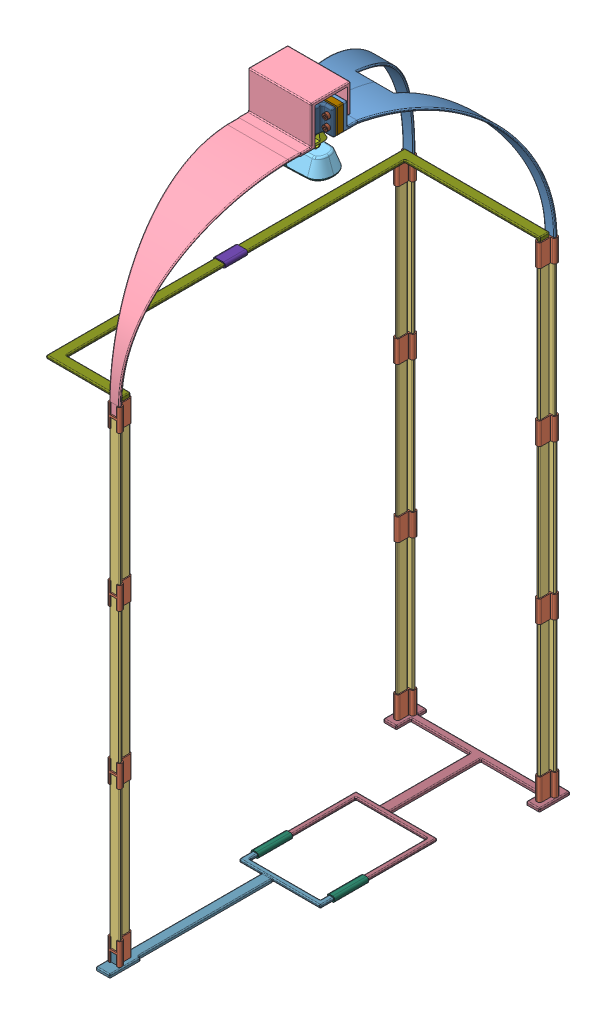
SolidWorks assembly cam-pied, configuration Défaut. Lengths in mm.
Overall size (156.53 671.2 384.16).
68 component instances, 17 part files, 139 mates.
Components (placement in the parent):
- cam-pied-droit-1-1: cam-pied-droit-1 [Défaut] at (-24.3914 -23.7361 180.8499) x (-1 0 0) z (0 0 -1) size (78.27 185 176.21)
  - cam-pied-droit-1: cam-pied-droit [Défaut] at (-220.0345 188.3747 308) size (156.53 186.65 177.66)
- cam-pied-droit-2-1: cam-pied-droit-2 [Défaut] at (-24.3914 -23.7361 180.8499) x (-1 0 0) z (0 0 -1) size (78.27 186.65 177.66)
  - cam-pied-droit-1: cam-pied-droit [Défaut] at (-220.0345 188.3747 308) size (156.53 186.65 177.66)
- cam-pied-joint-1: cam-pied-joint [Défaut] at (195.7432 4.6385 66.4499) x (1 0 0) z (0 1 0) size (12.2 16.4 22)
- cam-pied-joint-2: cam-pied-joint [Défaut] at (265.6432 2.6385 -292.5501) x (1 0 0) z (0 -1 0) size (12.2 16.4 22)
- cam-pied-joint-3: cam-pied-joint [Défaut] at (125.6432 2.6385 -292.7501) x (1 0 0) z (0 -1 0) size (12.2 16.4 22)
- cam-pied-joint-4: cam-pied-joint [Défaut] at (265.6432 -149.3615 -292.5501) x (1 0 0) z (0 -1 0) size (12.2 16.4 22)
- cam-pied-joint-5: cam-pied-joint [Défaut] at (125.8432 -301.3615 -292.7501) x (1 0 0) z (0 -1 0) size (12.2 16.4 22)
- cam-pied-joint-6: cam-pied-joint [Défaut] at (265.6432 -301.3615 -292.5501) x (1 0 0) z (0 -1 0) size (12.2 16.4 22)
- cam-pied-joint-7: cam-pied-joint [Défaut] at (125.6432 -149.3615 -292.7501) x (1 0 0) z (0 -1 0) size (12.2 16.4 22)
- cam-pied-joint-8: cam-pied-joint [Défaut] at (195.7432 -147.3615 66.4499) x (1 0 0) z (0 1 0) size (12.2 16.4 22)
- cam-pied-joint-9: cam-pied-joint [Défaut] at (195.7432 -299.3615 66.4499) x (1 0 0) z (0 1 0) size (12.2 16.4 22)
- cam-pied-montant-1: cam-pied-montant [Défaut] at (195.8432 -147.3615 66.3499) x (1 0 0) z (0 1 0) size (10 3 150)
- cam-pied-montant-2: cam-pied-montant [Défaut] at (195.6432 -299.3615 66.3499) x (1 0 0) z (0 1 0) size (10 3 150)
- cam-pied-montant-3: cam-pied-montant [Défaut] at (195.8432 -147.3615 58.6499) x (0 0 -1) z (0 1 0) size (10 3 150)
- cam-pied-montant-4: cam-pied-montant [Défaut] at (195.8432 -299.3615 58.6499) x (0 0 1) z (0 1 0) size (10 3 150)
- cam-pied-montant-5: cam-pied-montant [Défaut] at (265.7432 -299.3615 -284.7501) x (0 0 -1) z (0 1 0) size (10 3 150)
- cam-pied-montant-6: cam-pied-montant [Défaut] at (265.7432 -149.3615 -292.4501) x (1 0 0) z (0 -1 0) size (10 3 150)
- cam-pied-montant-7: cam-pied-montant [Défaut] at (125.7432 -147.3615 -285.1501) x (0 0 -1) z (0 1 0) size (10 3 150)
- cam-pied-montant-8: cam-pied-montant [Défaut] at (125.7432 -299.3615 -285.1501) x (0 0 1) z (0 1 0) size (10 3 150)
- cam-pied-montant-9: cam-pied-montant [Défaut] at (125.7432 -149.3615 -292.6501) x (1 0 0) z (0 -1 0) size (10 3 150)
- cam-pied-montant-10: cam-pied-montant [Défaut] at (265.5432 -147.3615 -292.4501) x (1 0 0) z (0 1 0) size (10 3 150)
- cam-pied-montant-11: cam-pied-montant [Défaut] at (125.5432 2.6385 -292.6501) x (1 0 0) z (0 -1 0) size (10 3 150)
- cam-pied-montant-12: cam-pied-montant [Défaut] at (265.7432 2.6385 -284.9501) x (0 0 -1) z (0 -1 0) size (10 3 150)
- cam-pied-gauche-1: cam-pied-gauche [Défaut] at (195.6432 164.6385 -99.1501) size (81.23 201.44 213.44)
- cam-c310-monte-1: cam-c310-monte [Défaut] at (194.893 183.199 -97.427) x (-1 0 0) z (0 1 0) size (71.5 31.83 69.48)
  - c310-1: c310 [Défaut] at (4.1302 -12.061 -110.284) x (-1 0 0) z (0 0 1) size (71.5 31.65 69.48)
    - c310-corps-1: c310-corps [Default] at (1.7129 6.6622 61.3001) size (71.27 31.35 30.56)
    - c310-cache-1: c310-cache [Default] at (1.7129 6.6622 59.0501) x (-1 0 0) z (0 0 -1) size (71.5 31.65 2.5)
    - clip-1-1: clip-1 [Default] at (4.1303 6.6622 81.7235) x (-1 0 0) z (0 0 1) size (43.19 23.62 48.27)
    - clip-2-1: clip-2 [Default] at (4.8803 2.4122 105.5985) x (-1 0 0) z (0 0 -1) size (36 14.88 39.47)
  - cam-mount-1-1: cam-mount-1 [Défaut] at (-0.7501 -29.7231 -6.0605) size (62 8 37)
  - cam-mount-2-1: cam-mount-2 [Défaut] at (-0.7501 -22.2204 -18.5605) size (62 19.5 37)
  - vis-chc-1: vis-chc [Vis CHC M3x10] at (25.2468 -19.2204 -1.0605) x (1 0 0) z (0 0 1) size (5.5 13 5.5)
  - vis-chc-2: vis-chc [Vis CHC M3x10] at (25.2468 -19.2204 -11.0605) x (1 0 0) z (0 0 1) size (5.5 13 5.5)
  - ecrou-h-1: ecrou-h [6012 HU M3] at (25.2468 -26.7231 -11.0605) x (0.5 0 -0.866025) z (0.866025 0 0.5) size (5.5 2.4 6.35)
  - vis-chc-3: vis-chc [Vis CHC M3x10] at (-26.7501 -19.2204 -1.0605) x (0.999999 0 -0.001191) z (0.001191 0 0.999999) size (5.5 13 5.5)
  - vis-chc-4: vis-chc [Vis CHC M3x10] at (-26.7501 -19.2204 -11.0605) x (0.814665 0 0.579932) z (-0.579932 0 0.814665) size (5.5 13 5.5)
  - ecrou-h-2: ecrou-h [6012 HU M3] at (25.2468 -26.7231 -1.0605) x (0.5 0 -0.866025) z (0.866025 0 0.5) size (5.5 2.4 6.35)
  - ecrou-h-3: ecrou-h [6012 HU M3] at (-26.7501 -26.7231 -1.0605) x (0.5 0 -0.866025) z (0.866025 0 0.5) size (5.5 2.4 6.35)
  - ecrou-h-4: ecrou-h [6012 HU M3] at (-26.7501 -26.7231 -11.0605) x (0.5 0 0.866025) z (-0.866025 0 0.5) size (5.5 2.4 6.35)
- vis-chc-1: vis-chc [Vis CHC M3x10] at (179.6432 182.1385 -134.1501) x (0.923728 0.383049 0) z (-0.383049 0.923728 0) size (5.5 13 5.5)
- vis-chc-2: vis-chc [Vis CHC M3x10] at (179.6432 172.1385 -131.1501) x (0.923728 0.383049 0) z (-0.383049 0.923728 0) size (5.5 13 5.5)
- vis-chc-3: vis-chc [Vis CHC M3x10] at (211.6432 172.1385 -131.1501) x (0.923728 0.383049 0) z (-0.383049 0.923728 0) size (5.5 13 5.5)
- vis-chc-4: vis-chc [Vis CHC M3x10] at (211.6432 182.1385 -134.1501) x (0.923728 0.383049 0) z (-0.383049 0.923728 0) size (5.5 13 5.5)
- ecrou-h-1: ecrou-h [6012 HU M3] at (211.6432 172.1385 -121.7501) x (-0.866025 0.5 0) z (0.5 0.866025 0) size (5.5 2.4 6.35)
- ecrou-h-2: ecrou-h [6012 HU M3] at (179.6432 172.1385 -121.7501) x (0 1 0) z (1 0 0) size (5.5 2.4 6.35)
- ecrou-h-3: ecrou-h [6012 HU M3] at (179.6432 182.1385 -121.7501) x (-0.866025 0.5 0) z (0.5 0.866025 0) size (5.5 2.4 6.35)
- ecrou-h-4: ecrou-h [6012 HU M3] at (211.6432 182.1385 -121.7501) x (0 1 0) z (1 0 0) size (5.5 2.4 6.35)
- cam-pied-joint-10: cam-pied-joint [Défaut] at (195.7432 -451.3615 66.4499) x (1 0 0) z (0 1 0) size (12.2 16.4 22)
- cam-pied-joint-11: cam-pied-joint [Défaut] at (125.7432 -453.3615 -292.7501) x (1 0 0) z (0 -1 0) size (12.2 16.4 22)
- cam-pied-joint-12: cam-pied-joint [Défaut] at (265.7432 -453.3615 -292.7501) x (1 0 0) z (0 -1 0) size (12.2 16.4 22)
- cam-socle-droit-2: cam-socle-droit [Défaut] at (195.8432 -463.3615 -292.6501) x (0 0 1) z (-1 0 0) size (185 13 154)
- cam-socle-gauche-1: cam-socle-gauche [Défaut] at (195.8432 -463.3615 67.8499) x (0 0 -1) z (1 0 0) size (185 14 80)
- cam-socle-joint-1: cam-socle-joint [Défaut] at (245.7432 -463.9615 -105.6501) size (7.2 5.2 33.5)
- cam-socle-joint-2: cam-socle-joint [Défaut] at (170.7432 -463.9615 -105.6501) size (7.2 5.2 33.5)
- cam-contreventement-1-2: cam-contreventement-1 [Défaut] at (549.3332 86.3011 -61.2162) x (0 0 -1) z (-1 0 0) size (175.8 14 73.11)
  - cam-contreventement-1: cam-contreventement [Défaut] at (218.7339 70.6625 353.6) size (353.6 14 143)
- cam-contreventement-2-1: cam-contreventement-2 [Défaut] at (549.3432 86.3011 -61.2162) x (0 0 -1) z (-1 0 0) size (175.8 14 143)
  - cam-contreventement-1: cam-contreventement [Défaut] at (218.7339 70.6625 353.6) size (353.6 14 143)
- cam-contreventement-joint-1: cam-contreventement-joint [Défaut] at (129.2332 17.1385 -112.1501) size (12 5 22)
- cam-pied-montant-13: cam-pied-montant [Défaut] at (195.8432 -451.3615 66.3499) x (1 0 0) z (0 1 0) size (10 3 150)
- cam-pied-montant-14: cam-pied-montant [Défaut] at (195.8432 -451.3615 58.8499) x (0 0 1) z (0 1 0) size (10 3 150)
- cam-pied-montant-15: cam-pied-montant [Défaut] at (125.9432 -451.3615 -292.6501) x (1 0 0) z (0 1 0) size (10 3 150)
- cam-pied-montant-16: cam-pied-montant [Défaut] at (125.8432 -451.3615 -284.9501) x (0 0 1) z (0 1 0) size (10 3 150)
- cam-pied-montant-17: cam-pied-montant [Défaut] at (265.7432 -451.3615 -292.4501) x (1 0 0) z (0 1 0) size (10 3 150)
- cam-pied-montant-18: cam-pied-montant [Défaut] at (265.7432 -451.3615 -284.9501) x (0 0 1) z (0 1 0) size (10 3 150)
Mates (geometry in assembly coordinates):
- Coïncidente18: coincident anti-aligned: plane of cam-pied-partie3-1/cam-pied-droit-1 through (120.6432 14.6385 -294.1501) normal (0 0 -1); plane of cam-pied-joint-v3-2 through (269.7432 14.6385 -294.1501) normal (0 0 1)
- Coïncidente19: coincident anti-aligned: plane of cam-pied-partie4-1/cam-pied-droit-1 through (120.6432 14.6385 -291.1501) normal (0 0 1); plane of cam-pied-joint-v3-3 through (121.5432 14.6385 -291.1501) normal (0 0 -1)
- Distance5: distance = 0.1 mm anti-aligned: plane of cam-pied-joint-v3-3 through (130.7432 14.6385 -292.1501) normal (-1 0 0); plane of cam-pied-partie4-1/cam-pied-droit-1 through (130.6432 14.6385 -127.1501) normal (1 0 0)
- Distance6: distance = 0.1 mm anti-aligned: plane of cam-pied-joint-v3-2 through (270.7432 14.6385 -291.9501) normal (-1 0 0); plane of cam-pied-partie3-1/cam-pied-droit-1 through (270.6432 164.6385 -127.1501) normal (1 0 0)
- Coïncidente49: coincident anti-aligned: plane of cam-pied-joint-1 through (191.6432 -7.3615 64.8499) normal (0 0 1); plane of cam-pied-montant-1 through (191.8432 2.6385 64.8499) normal (0 0 -1)
- Coïncidente50: coincident anti-aligned: plane of cam-pied-joint-1 through (200.8432 -7.3615 65.8499) normal (-1 0 0); plane of cam-pied-montant-1 through (200.8432 2.6385 65.8499) normal (1 0 0)
- Coïncidente51: coincident anti-aligned: plane of cam-pied-joint-1 through (199.8432 2.6385 65.8499) normal (0 -1 0); plane of cam-pied-montant-1 through (199.8432 2.6385 65.8499) normal (0 1 0)
- Coïncidente52: coincident anti-aligned: plane of cam-pied-joint-8 through (191.6432 -137.3615 64.8499) normal (0 0 1); plane of cam-pied-montant-1 through (191.8432 2.6385 64.8499) normal (0 0 -1)
- Coïncidente53: coincident anti-aligned: plane of cam-pied-joint-8 through (200.8432 -137.3615 65.8499) normal (-1 0 0); plane of cam-pied-montant-1 through (200.8432 2.6385 65.8499) normal (1 0 0)
- Coïncidente54: coincident anti-aligned: plane of cam-pied-joint-8 through (199.8432 -147.3615 65.8499) normal (0 1 0); plane of cam-pied-montant-1 through (199.8432 -147.3615 65.8499) normal (0 -1 0)
- Coïncidente55: coincident anti-aligned: plane of cam-pied-joint-1 through (197.3432 -7.3615 62.8499) normal (-1 0 0); plane of cam-pied-montant-3 through (197.3432 2.6385 62.6499) normal (1 0 0)
- Coïncidente56: coincident anti-aligned: plane of cam-pied-joint-1 through (195.1432 -7.3615 53.6499) normal (0 0 1); plane of cam-pied-montant-3 through (195.3432 2.6385 53.6499) normal (0 0 -1)
- Coïncidente57: coincident anti-aligned: plane of cam-pied-joint-1 through (199.8432 2.6385 65.8499) normal (0 -1 0); plane of cam-pied-montant-3 through (195.3432 2.6385 54.6499) normal (0 1 0)
- Coïncidente58: coincident anti-aligned: plane of cam-pied-joint-8 through (191.6432 -159.3615 64.8499) normal (0 0 1); plane of cam-pied-montant-2 through (191.6432 -149.3615 64.8499) normal (0 0 -1)
- Coïncidente59: coincident anti-aligned: plane of cam-pied-joint-8 through (190.6432 -159.3615 67.0499) normal (1 0 0); plane of cam-pied-montant-2 through (190.6432 -149.3615 65.8499) normal (-1 0 0)
- Coïncidente60: coincident anti-aligned: plane of cam-pied-joint-8 through (199.8432 -149.3615 65.8499) normal (0 -1 0); plane of cam-pied-montant-2 through (199.6432 -149.3615 65.8499) normal (0 1 0)
- Coïncidente61: coincident anti-aligned: plane of cam-pied-joint-9 through (191.6432 -289.3615 64.8499) normal (0 0 1); plane of cam-pied-montant-2 through (191.6432 -149.3615 64.8499) normal (0 0 -1)
- Coïncidente62: coincident anti-aligned: plane of cam-pied-joint-9 through (190.6432 -289.3615 67.0499) normal (1 0 0); plane of cam-pied-montant-2 through (190.6432 -149.3615 65.8499) normal (-1 0 0)
- Coïncidente63: coincident anti-aligned: plane of cam-pied-joint-9 through (199.8432 -299.3615 65.8499) normal (0 1 0); plane of cam-pied-montant-2 through (199.6432 -299.3615 65.8499) normal (0 -1 0)
- Coïncidente64: coincident anti-aligned: plane of cam-pied-joint-8 through (197.3432 -159.3615 62.8499) normal (-1 0 0); plane of cam-pied-montant-4 through (197.3432 -149.3615 54.6499) normal (1 0 0)
- Coïncidente65: coincident anti-aligned: plane of cam-pied-joint-8 through (195.1432 -159.3615 53.6499) normal (0 0 1); plane of cam-pied-montant-4 through (196.3432 -149.3615 53.6499) normal (0 0 -1)
- Coïncidente66: coincident anti-aligned: plane of cam-pied-joint-8 through (199.8432 -149.3615 65.8499) normal (0 -1 0); plane of cam-pied-montant-4 through (196.3432 -149.3615 62.6499) normal (0 1 0)
- Coïncidente67: coincident anti-aligned: plane of cam-pied-droit-2-1/cam-pied-droit-1 through (120.6432 4.6385 -291.1501) normal (0 -1 0); plane of cam-pied-joint-3 through (129.7432 4.6385 -292.1501) normal (0 1 0)
- Coïncidente68: coincident anti-aligned: plane of cam-pied-droit-1-1/cam-pied-droit-1 through (120.6432 4.6385 -291.1501) normal (0 -1 0); plane of cam-pied-joint-2 through (269.7432 4.6385 -291.9501) normal (0 1 0)
- Coïncidente69: coincident anti-aligned: plane of cam-pied-joint-2 through (267.2432 -7.3615 -288.9501) normal (-1 0 0); plane of cam-pied-montant-12 through (267.2432 -147.3615 -280.9501) normal (1 0 0)
- Coïncidente70: coincident anti-aligned: plane of cam-pied-joint-2 through (265.0432 -7.3615 -289.9501) normal (0 0 1); plane of cam-pied-montant-12 through (266.2432 -147.3615 -289.9501) normal (0 0 -1)
- Coïncidente71: coincident anti-aligned: plane of cam-pied-joint-2 through (269.7432 2.6385 -291.9501) normal (0 -1 0); plane of cam-pied-montant-12 through (266.2432 2.6385 -288.9501) normal (0 1 0)
- Coïncidente72: coincident anti-aligned: plane of cam-pied-joint-2 through (261.5432 -7.3615 -290.9501) normal (0 0 -1); plane of cam-pied-montant-10 through (261.5432 2.6385 -290.9501) normal (0 0 1)
- Coïncidente73: coincident anti-aligned: plane of cam-pied-joint-2 through (260.5432 -7.3615 -293.1501) normal (1 0 0); plane of cam-pied-montant-10 through (260.5432 2.6385 -292.9501) normal (-1 0 0)
- Coïncidente74: coincident anti-aligned: plane of cam-pied-joint-2 through (269.7432 2.6385 -291.9501) normal (0 -1 0); plane of cam-pied-montant-10 through (269.5432 2.6385 -292.9501) normal (0 1 0)
- Coïncidente75: coincident anti-aligned: plane of cam-pied-joint-4 through (261.5432 -159.3615 -290.9501) normal (0 0 -1); plane of cam-pied-montant-10 through (261.5432 2.6385 -290.9501) normal (0 0 1)
- Coïncidente76: coincident anti-aligned: plane of cam-pied-joint-4 through (260.5432 -159.3615 -293.1501) normal (1 0 0); plane of cam-pied-montant-10 through (260.5432 2.6385 -292.9501) normal (-1 0 0)
- Coïncidente77: coincident anti-aligned: plane of cam-pied-joint-4 through (269.7432 -147.3615 -291.9501) normal (0 1 0); plane of cam-pied-montant-10 through (269.5432 -147.3615 -292.9501) normal (0 -1 0)
- Coïncidente78: coincident anti-aligned: plane of cam-pied-joint-4 through (261.5432 -159.3615 -290.9501) normal (0 0 -1); plane of cam-pied-montant-6 through (261.7432 -299.3615 -290.9501) normal (0 0 1)
- Coïncidente79: coincident anti-aligned: plane of cam-pied-joint-4 through (270.7432 -159.3615 -291.9501) normal (-1 0 0); plane of cam-pied-montant-6 through (270.7432 -299.3615 -291.9501) normal (1 0 0)
- Coïncidente80: coincident anti-aligned: plane of cam-pied-joint-4 through (269.7432 -149.3615 -291.9501) normal (0 -1 0); plane of cam-pied-montant-6 through (269.7432 -149.3615 -291.9501) normal (0 1 0)
- Coïncidente81: coincident anti-aligned: plane of cam-pied-joint-6 through (261.5432 -289.3615 -290.9501) normal (0 0 -1); plane of cam-pied-montant-6 through (261.7432 -299.3615 -290.9501) normal (0 0 1)
- Coïncidente82: coincident anti-aligned: plane of cam-pied-joint-6 through (270.7432 -289.3615 -291.9501) normal (-1 0 0); plane of cam-pied-montant-6 through (270.7432 -299.3615 -291.9501) normal (1 0 0)
- Coïncidente83: coincident anti-aligned: plane of cam-pied-joint-6 through (269.7432 -299.3615 -291.9501) normal (0 1 0); plane of cam-pied-montant-6 through (269.7432 -299.3615 -291.9501) normal (0 -1 0)
- Coïncidente84: coincident anti-aligned: plane of cam-pied-joint-4 through (267.2432 -159.3615 -288.9501) normal (-1 0 0); plane of cam-pied-montant-5 through (267.2432 -149.3615 -280.7501) normal (1 0 0)
- Coïncidente85: coincident anti-aligned: plane of cam-pied-joint-4 through (265.0432 -159.3615 -279.7501) normal (0 0 -1); plane of cam-pied-montant-5 through (265.2432 -149.3615 -279.7501) normal (0 0 1)
- Coïncidente86: coincident anti-aligned: plane of cam-pied-joint-4 through (269.7432 -149.3615 -291.9501) normal (0 -1 0); plane of cam-pied-montant-5 through (265.2432 -149.3615 -288.7501) normal (0 1 0)
- Coïncidente87: coincident anti-aligned: plane of cam-pied-joint-3 through (121.5432 -7.3615 -291.1501) normal (0 0 -1); plane of cam-pied-montant-11 through (121.5432 -147.3615 -291.1501) normal (0 0 1)
- Coïncidente88: coincident anti-aligned: plane of cam-pied-joint-3 through (120.5432 -7.3615 -293.3501) normal (1 0 0); plane of cam-pied-montant-11 through (120.5432 -147.3615 -292.1501) normal (-1 0 0)
- Coïncidente89: coincident anti-aligned: plane of cam-pied-joint-3 through (129.7432 2.6385 -292.1501) normal (0 -1 0); plane of cam-pied-montant-11 through (129.5432 2.6385 -292.1501) normal (0 1 0)
- Coïncidente90: coincident anti-aligned: plane of cam-pied-joint-7 through (120.5432 -137.3615 -293.3501) normal (1 0 0); plane of cam-pied-montant-11 through (120.5432 -147.3615 -292.1501) normal (-1 0 0)
- Coïncidente91: coincident anti-aligned: plane of cam-pied-joint-7 through (121.5432 -137.3615 -291.1501) normal (0 0 -1); plane of cam-pied-montant-11 through (121.5432 -147.3615 -291.1501) normal (0 0 1)
- Coïncidente92: coincident anti-aligned: plane of cam-pied-joint-7 through (129.7432 -147.3615 -292.1501) normal (0 1 0); plane of cam-pied-montant-11 through (129.5432 -147.3615 -292.1501) normal (0 -1 0)
- Coïncidente93: coincident anti-aligned: plane of cam-pied-joint-3 through (127.2432 -7.3615 -289.1501) normal (-1 0 0); plane of cam-pied-montant-7 through (127.2432 2.6385 -281.1501) normal (1 0 0)
- Coïncidente94: coincident anti-aligned: plane of cam-pied-joint-3 through (125.0432 -7.3615 -290.1501) normal (0 0 1); plane of cam-pied-montant-7 through (125.2432 2.6385 -290.1501) normal (0 0 -1)
- Coïncidente95: coincident anti-aligned: plane of cam-pied-joint-3 through (129.7432 2.6385 -292.1501) normal (0 -1 0); plane of cam-pied-montant-7 through (125.2432 2.6385 -289.1501) normal (0 1 0)
- Coïncidente96: coincident anti-aligned: plane of cam-pied-joint-7 through (127.2432 -159.3615 -289.1501) normal (-1 0 0); plane of cam-pied-montant-8 through (127.2432 -149.3615 -289.1501) normal (1 0 0)
- Coïncidente97: coincident anti-aligned: plane of cam-pied-joint-7 through (125.0432 -159.3615 -290.1501) normal (0 0 1); plane of cam-pied-montant-8 through (126.2432 -149.3615 -290.1501) normal (0 0 -1)
- Coïncidente98: coincident anti-aligned: plane of cam-pied-joint-7 through (129.7432 -149.3615 -292.1501) normal (0 -1 0); plane of cam-pied-montant-8 through (126.2432 -149.3615 -281.1501) normal (0 1 0)
- Coïncidente99: coincident anti-aligned: plane of cam-pied-joint-7 through (121.5432 -159.3615 -291.1501) normal (0 0 -1); plane of cam-pied-montant-9 through (121.7432 -299.3615 -291.1501) normal (0 0 1)
- Coïncidente100: coincident anti-aligned: plane of cam-pied-joint-7 through (130.7432 -159.3615 -292.1501) normal (-1 0 0); plane of cam-pied-montant-9 through (130.7432 -299.3615 -292.1501) normal (1 0 0)
- Coïncidente101: coincident anti-aligned: plane of cam-pied-joint-7 through (129.7432 -149.3615 -292.1501) normal (0 -1 0); plane of cam-pied-montant-9 through (129.7432 -149.3615 -292.1501) normal (0 1 0)
- Coaxiale5: concentric aligned: cylinder of cam-pied-droit-2-1/cam-pied-droit-1 through (179.6432 182.1385 -127.1501) axis (0 0 -1) radius 1.6; cylinder of cam-pied-gauche-1 through (179.6432 182.1385 -126.6246) axis (0 0 -1) radius 1.6
- Coïncidente103: coincident anti-aligned: plane of cam-pied-droit-2-1/cam-pied-droit-1 through (195.6432 164.6385 -131.1501) normal (0 0 -1); plane of cam-pied-gauche-1 through (226.6432 176.6385 -131.1501) normal (0 0 1)
- Coaxiale6: concentric aligned: cylinder of cam-pied-droit-1-1/cam-pied-droit-1 through (211.6432 182.1385 -127.1501) axis (0 0 -1) radius 1.6; cylinder of cam-pied-gauche-1 through (211.6432 182.1385 -126.6246) axis (0 0 -1) radius 1.6
- Coïncidente104: coincident anti-aligned: plane of cam-pied-droit-1-1/cam-pied-droit-1 through (195.6432 164.6385 -131.1501) normal (0 0 -1); plane of cam-pied-gauche-1 through (226.6432 176.6385 -131.1501) normal (0 0 1)
- Coïncidente105: coincident anti-aligned: plane of cam-pied-droit-1-1/cam-pied-droit-1 through (195.6432 -23.7361 180.8499) normal (-1 0 0); plane of cam-pied-droit-2-1/cam-pied-droit-1 through (195.6432 -23.7361 180.8499) normal (1 0 0)
- Coïncidente106: coincident anti-aligned: plane of cam-pied-joint-1 through (191.6432 14.6385 64.8499) normal (0 0 1); plane of cam-pied-gauche-1 through (270.6432 14.6385 64.8499) normal (0 0 -1)
- Coïncidente107: coincident anti-aligned: plane of cam-pied-joint-1 through (190.6432 14.6385 67.0499) normal (1 0 0); plane of cam-pied-gauche-1 through (190.6432 -263.8698 -134.1501) normal (-1 0 0)
- Coïncidente108: coincident anti-aligned: plane of cam-pied-joint-1 through (199.8432 4.6385 65.8499) normal (0 1 0); plane of cam-pied-gauche-1 through (270.6432 4.6385 64.8499) normal (0 -1 0)
- Coïncidente109: coincident anti-aligned: plane of cam-pied-joint-5 through (121.7432 -289.3615 -291.1501) normal (0 0 -1); plane of cam-pied-montant-9 through (121.7432 -299.3615 -291.1501) normal (0 0 1)
- Coïncidente110: coincident anti-aligned: plane of cam-pied-joint-5 through (120.7432 -289.3615 -293.3501) normal (1 0 0); plane of cam-pied-montant-9 through (120.7432 -299.3615 -292.1501) normal (-1 0 0)
- Coïncidente111: coincident anti-aligned: plane of cam-pied-joint-5 through (129.9432 -299.3615 -292.1501) normal (0 1 0); plane of cam-pied-montant-9 through (129.7432 -299.3615 -292.1501) normal (0 -1 0)
- Coïncidente112: coincident anti-aligned: plane of cam-pied-droit-1-1/cam-pied-droit-1 through (195.6432 164.6385 -127.1501) normal (0 0 1); plane of cam-c310-monte-1/cam-mount-1-1 through (195.6432 177.1385 -127.1501) normal (0 0 -1)
- Coaxiale7: concentric anti-aligned: cylinder of cam-pied-gauche-1 through (211.6432 182.1385 -126.6246) axis (0 0 -1) radius 1.6; cylinder of cam-c310-monte-1/cam-mount-1-1 through (211.6432 182.1385 -127.1501) axis (0 0 1) radius 1.6
- Coaxiale8: concentric anti-aligned: cylinder of cam-pied-gauche-1 through (179.6432 182.1385 -126.6246) axis (0 0 -1) radius 1.6; cylinder of cam-c310-monte-1/cam-mount-1-1 through (179.6432 182.1385 -127.1501) axis (0 0 1) radius 1.6
- Coaxiale9: concentric aligned: cylinder of cam-pied-gauche-1 through (211.6432 182.1385 -126.6246) axis (0 0 -1) radius 1.6; cylinder of vis-chc-4 through (211.6432 182.1385 -124.1501) axis (0 0 -1) radius 1.5
- Coaxiale10: concentric aligned: cylinder of cam-pied-gauche-1 through (179.6432 182.1385 -126.6246) axis (0 0 -1) radius 1.6; cylinder of vis-chc-1 through (179.6432 182.1385 -124.1501) axis (0 0 -1) radius 1.5
- Coaxiale11: concentric aligned: cylinder of cam-pied-droit-2-1/cam-pied-droit-1 through (179.6432 172.1385 -127.1501) axis (0 0 -1) radius 1.6; cylinder of vis-chc-2 through (179.6432 172.1385 -121.1501) axis (0 0 -1) radius 1.5
- Coaxiale12: concentric aligned: cylinder of cam-pied-droit-1-1/cam-pied-droit-1 through (211.6432 172.1385 -127.1501) axis (0 0 -1) radius 1.6; cylinder of vis-chc-3 through (211.6432 172.1385 -121.1501) axis (0 0 -1) radius 1.5
- Coïncidente113: coincident anti-aligned: plane of cam-pied-gauche-1 through (195.6432 164.6385 -134.1501) normal (0 0 -1); plane of vis-chc-4 through (211.6432 182.1385 -134.1501) normal (0 0 1)
- Coïncidente114: coincident anti-aligned: plane of cam-pied-gauche-1 through (195.6432 164.6385 -134.1501) normal (0 0 -1); plane of vis-chc-1 through (179.6432 182.1385 -134.1501) normal (0 0 1)
- Coïncidente115: coincident anti-aligned: plane of cam-pied-droit-2-1/cam-pied-droit-1 through (195.6432 164.6385 -131.1501) normal (0 0 -1); plane of vis-chc-2 through (179.6432 172.1385 -131.1501) normal (0 0 1)
- Coïncidente116: coincident anti-aligned: plane of cam-pied-droit-1-1/cam-pied-droit-1 through (195.6432 164.6385 -131.1501) normal (0 0 -1); plane of vis-chc-3 through (211.6432 172.1385 -131.1501) normal (0 0 1)
- Coïncidente117: coincident anti-aligned: plane of cam-c310-monte-1/cam-mount-1-1 through (195.6432 177.1385 -124.1501) normal (0 0 1); plane of ecrou-h-4 through (210.0554 184.8885 -124.1501) normal (0 0 -1)
- Coaxiale14: concentric aligned: cylinder of cam-c310-monte-1/cam-mount-1-1 through (211.6432 182.1385 -127.1501) axis (0 0 1) radius 1.6; cylinder of ecrou-h-4 through (211.6432 182.1385 -124.1501) axis (0 0 1) radius 1.2295
- Parallèle1: parallel anti-aligned: plane of cam-c310-monte-1/cam-mount-1-1 through (213.3932 179.1074 -124.1501) normal (-0.866025 0.5 0); plane of ecrou-h-4 through (213.2309 179.3885 -124.1501) normal (0.866025 -0.5 0)
- Coïncidente119: coincident anti-aligned: plane of cam-c310-monte-1/cam-mount-1-1 through (195.6432 177.1385 -124.1501) normal (0 0 1); plane of ecrou-h-1 through (208.4677 172.1385 -124.1501) normal (0 0 -1)
- Coaxiale15: concentric anti-aligned: cylinder of vis-chc-3 through (211.6432 172.1385 -121.1501) axis (0 0 -1) radius 1.5; cylinder of ecrou-h-1 through (211.6432 172.1385 -124.1501) axis (0 0 1) radius 1.2295
- Parallèle2: parallel anti-aligned: plane of cam-c310-monte-1/cam-mount-1-1 through (213.3932 175.1696 -124.1501) normal (0 -1 0); plane of ecrou-h-1 through (213.2309 174.8885 -124.1501) normal (0 1 0)
- Coïncidente121: coincident anti-aligned: plane of cam-c310-monte-1/cam-mount-1-1 through (195.6432 177.1385 -124.1501) normal (0 0 1); plane of ecrou-h-2 through (178.0554 174.8885 -124.1501) normal (0 0 -1)
- Coaxiale16: concentric anti-aligned: cylinder of vis-chc-2 through (179.6432 172.1385 -121.1501) axis (0 0 -1) radius 1.5; cylinder of ecrou-h-2 through (179.6432 172.1385 -124.1501) axis (0 0 1) radius 1.2295
- Parallèle3: parallel anti-aligned: plane of cam-c310-monte-1/cam-mount-1-1 through (183.1432 172.1385 -124.1501) normal (-0.866025 -0.5 0); plane of ecrou-h-2 through (182.8186 172.1385 -124.1501) normal (0.866025 0.5 0)
- Coïncidente124: coincident anti-aligned: plane of cam-c310-monte-1/cam-mount-1-1 through (195.6432 177.1385 -124.1501) normal (0 0 1); plane of ecrou-h-3 through (176.4677 182.1385 -124.1501) normal (0 0 -1)
- Coaxiale17: concentric anti-aligned: cylinder of vis-chc-1 through (179.6432 182.1385 -124.1501) axis (0 0 -1) radius 1.5; cylinder of ecrou-h-3 through (179.6432 182.1385 -124.1501) axis (0 0 1) radius 1.2295
- Parallèle4: parallel anti-aligned: plane of cam-c310-monte-1/cam-mount-1-1 through (183.1432 182.1385 -124.1501) normal (-0.866025 -0.5 0); plane of ecrou-h-3 through (182.8186 182.1385 -124.1501) normal (0.866025 0.5 0)
- Coïncidente156: coincident anti-aligned: plane of cam-socle-droit-2 through (129.8432 -453.3615 -291.1501) normal (0 0 1); plane of cam-pied-joint-11 through (121.6432 -463.3615 -291.1501) normal (0 0 -1)
- Coïncidente158: coincident anti-aligned: plane of cam-socle-droit-2 through (127.3432 -453.3615 -288.1501) normal (1 0 0); plane of cam-pied-joint-11 through (127.3432 -463.3615 -289.1501) normal (-1 0 0)
- Coïncidente160: coincident anti-aligned: plane of cam-pied-joint-10 through (191.6432 -463.3615 64.8499) normal (0 0 1); plane of cam-socle-gauche-1 through (191.8432 -452.3615 64.8499) normal (0 0 -1)
- Coïncidente161: coincident anti-aligned: plane of cam-pied-joint-10 through (197.3432 -463.3615 62.8499) normal (-1 0 0); plane of cam-socle-gauche-1 through (197.3432 -452.3615 61.8499) normal (1 0 0)
- Coïncidente162: coincident anti-aligned: plane of cam-pied-joint-10 through (199.8432 -463.3615 65.8499) normal (0 -1 0); plane of cam-socle-gauche-1 through (195.8432 -463.3615 67.8499) normal (0 1 0)
- Coïncidente163: coincident anti-aligned: plane of cam-pied-joint-1 through (197.3432 14.6385 62.8499) normal (-1 0 0); plane of cam-contreventement-1-2/cam-contreventement-1 through (197.3432 15.6385 -279.9501) normal (1 0 0)
- Coïncidente164: coincident anti-aligned: plane of cam-pied-joint-1 through (199.8432 4.6385 65.8499) normal (0 1 0); plane of cam-contreventement-1-2/cam-contreventement-1 through (265.2332 4.6385 -288.9501) normal (0 -1 0)
- Coïncidente166: coincident anti-aligned: plane of cam-pied-joint-1 through (195.1432 14.6385 53.6499) normal (0 0 1); plane of cam-contreventement-1-2/cam-contreventement-1 through (197.3432 18.6385 53.6499) normal (0 0 -1)
- Coïncidente167: coincident anti-aligned: plane of cam-pied-joint-2 through (269.7432 4.6385 -291.9501) normal (0 1 0); plane of cam-contreventement-2-1/cam-contreventement-1 through (265.2432 4.6385 -288.9501) normal (0 -1 0)
- Coïncidente168: coincident anti-aligned: plane of cam-pied-joint-2 through (267.2432 14.6385 -288.9501) normal (-1 0 0); plane of cam-contreventement-2-1/cam-contreventement-1 through (267.2432 18.6385 -279.9501) normal (1 0 0)
- Coïncidente169: coincident anti-aligned: plane of cam-pied-joint-3 through (125.0432 14.6385 -279.9501) normal (0 0 -1); plane of cam-contreventement-2-1/cam-contreventement-1 through (126.2432 4.6385 -279.9501) normal (0 0 1)
- Coïncidente171: coincident anti-aligned: plane of cam-contreventement-1-2/cam-contreventement-1 through (549.3332 86.3011 -112.1501) normal (0 0 -1); plane of cam-contreventement-joint-1 through (133.2332 17.6385 -112.1501) normal (0 0 1)
- Coïncidente172: coincident anti-aligned: plane of cam-contreventement-1-2/cam-contreventement-1 through (195.7332 18.6385 -279.9501) normal (0 1 0); plane of cam-contreventement-joint-1 through (125.2332 18.6385 -102.1501) normal (0 -1 0)
- Coïncidente173: coincident anti-aligned: plane of cam-contreventement-1-2/cam-contreventement-1 through (134.2332 18.6385 63.6499) normal (1 0 0); plane of cam-contreventement-joint-1 through (134.2332 17.6385 -102.1501) normal (-1 0 0)
- Coïncidente174: coincident anti-aligned: plane of cam-pied-joint-11 through (129.8432 -453.3615 -292.1501) normal (0 -1 0); plane of cam-socle-droit-2 through (121.8432 -453.3615 -293.1501) normal (0 1 0)
- Coïncidente175: coincident anti-aligned: plane of cam-socle-droit-2 through (168.3432 -462.3615 -192.6501) normal (0 1 0); plane of cam-socle-joint-1 through (244.1432 -462.3615 -129.1501) normal (0 -1 0)
- Coïncidente176: coincident anti-aligned: plane of cam-socle-droit-2 through (248.3432 -462.3615 -192.6501) normal (1 0 0); plane of cam-socle-joint-1 through (248.3432 -463.3615 -129.1501) normal (-1 0 0)
- Coïncidente177: coincident anti-aligned: plane of cam-socle-droit-2 through (195.8432 -463.3615 -119.1501) normal (0 0 1); plane of cam-socle-joint-1 through (247.3432 -463.3615 -119.1501) normal (0 0 -1)
- Coïncidente178: coincident anti-aligned: plane of cam-socle-droit-2 through (168.3432 -462.3615 -192.6501) normal (0 1 0); plane of cam-socle-joint-2 through (169.1432 -462.3615 -129.1501) normal (0 -1 0)
- Coïncidente179: coincident anti-aligned: plane of cam-socle-droit-2 through (195.8432 -463.3615 -119.1501) normal (0 0 1); plane of cam-socle-joint-2 through (172.3432 -463.3615 -119.1501) normal (0 0 -1)
- Coïncidente180: coincident anti-aligned: plane of cam-socle-droit-2 through (173.3432 -462.3615 -119.1501) normal (1 0 0); plane of cam-socle-joint-2 through (173.3432 -463.3615 -129.1501) normal (-1 0 0)
- Coïncidente183: coincident anti-aligned: plane of cam-pied-joint-9 through (199.8432 -301.3615 65.8499) normal (0 -1 0); plane of cam-pied-montant-13 through (199.8432 -301.3615 65.8499) normal (0 1 0)
- Coïncidente184: coincident anti-aligned: plane of cam-pied-joint-9 through (191.6432 -311.3615 64.8499) normal (0 0 1); plane of cam-pied-montant-13 through (191.8432 -301.3615 64.8499) normal (0 0 -1)
- Coïncidente185: coincident anti-aligned: plane of cam-pied-joint-9 through (200.8432 -311.3615 65.8499) normal (-1 0 0); plane of cam-pied-montant-13 through (200.8432 -301.3615 65.8499) normal (1 0 0)
- Coïncidente186: coincident anti-aligned: plane of cam-pied-joint-10 through (191.6432 -441.3615 64.8499) normal (0 0 1); plane of cam-pied-montant-13 through (191.8432 -301.3615 64.8499) normal (0 0 -1)
- Coïncidente187: coincident anti-aligned: plane of cam-pied-joint-10 through (199.8432 -451.3615 65.8499) normal (0 1 0); plane of cam-pied-montant-13 through (199.8432 -451.3615 65.8499) normal (0 -1 0)
- Coïncidente188: coincident anti-aligned: plane of cam-pied-joint-10 through (200.8432 -441.3615 65.8499) normal (-1 0 0); plane of cam-pied-montant-13 through (200.8432 -301.3615 65.8499) normal (1 0 0)
- Coïncidente189: coincident anti-aligned: plane of cam-pied-joint-10 through (197.3432 -441.3615 62.8499) normal (-1 0 0); plane of cam-pied-montant-14 through (197.3432 -301.3615 54.8499) normal (1 0 0)
- Coïncidente190: coincident anti-aligned: plane of cam-pied-joint-10 through (199.8432 -451.3615 65.8499) normal (0 1 0); plane of cam-pied-montant-14 through (196.3432 -451.3615 62.8499) normal (0 -1 0)
- Coïncidente191: coincident anti-aligned: plane of cam-pied-joint-10 through (195.1432 -441.3615 63.8499) normal (0 0 -1); plane of cam-pied-montant-14 through (196.3432 -301.3615 63.8499) normal (0 0 1)
- Coïncidente192: coincident anti-aligned: plane of cam-socle-gauche-1 through (248.3432 -462.3615 -87.6501) normal (0 1 0); plane of cam-socle-joint-1 through (244.1432 -462.3615 -95.6501) normal (0 -1 0)
- Coïncidente193: coincident anti-aligned: plane of cam-socle-gauche-1 through (195.8432 -463.3615 -105.6501) normal (0 0 -1); plane of cam-socle-joint-1 through (247.3432 -463.3615 -105.6501) normal (0 0 1)
- Coïncidente194: coincident anti-aligned: plane of cam-socle-gauche-1 through (248.3432 -462.3615 -87.6501) normal (1 0 0); plane of cam-socle-joint-1 through (248.3432 -463.3615 -95.6501) normal (-1 0 0)
- Coïncidente196: coincident anti-aligned: plane of cam-pied-joint-5 through (121.7432 -311.3615 -291.1501) normal (0 0 -1); plane of cam-pied-montant-15 through (121.9432 -301.3615 -291.1501) normal (0 0 1)
- Coïncidente197: coincident anti-aligned: plane of cam-pied-joint-5 through (130.9432 -311.3615 -292.1501) normal (-1 0 0); plane of cam-pied-montant-15 through (130.9432 -301.3615 -293.1501) normal (1 0 0)
- Coïncidente198: coincident anti-aligned: plane of cam-pied-joint-5 through (129.9432 -301.3615 -292.1501) normal (0 -1 0); plane of cam-pied-montant-15 through (129.9432 -301.3615 -293.1501) normal (0 1 0)
- Coïncidente199: coincident anti-aligned: plane of cam-pied-joint-11 through (127.3432 -441.3615 -289.1501) normal (-1 0 0); plane of cam-pied-montant-16 through (127.3432 -301.3615 -288.9501) normal (1 0 0)
- Coïncidente200: coincident anti-aligned: plane of cam-pied-joint-11 through (129.8432 -451.3615 -292.1501) normal (0 1 0); plane of cam-pied-montant-16 through (126.3432 -451.3615 -280.9501) normal (0 -1 0)
- Coïncidente201: coincident anti-aligned: plane of cam-pied-joint-11 through (125.1432 -441.3615 -279.9501) normal (0 0 -1); plane of cam-pied-montant-16 through (126.3432 -301.3615 -279.9501) normal (0 0 1)
- Coïncidente202: coincident anti-aligned: plane of cam-pied-joint-12 through (267.3432 -441.3615 -289.1501) normal (-1 0 0); plane of cam-socle-droit-2 through (267.3432 -453.3615 -288.1501) normal (1 0 0)
- Coïncidente203: coincident anti-aligned: plane of cam-pied-joint-12 through (261.6432 -463.3615 -291.1501) normal (0 0 -1); plane of cam-socle-droit-2 through (269.8432 -453.3615 -291.1501) normal (0 0 1)
- Coïncidente204: coincident anti-aligned: plane of cam-pied-joint-12 through (269.8432 -453.3615 -292.1501) normal (0 -1 0); plane of cam-socle-droit-2 through (261.8432 -453.3615 -292.1501) normal (0 1 0)
- Coïncidente205: coincident anti-aligned: plane of cam-pied-joint-6 through (261.5432 -311.3615 -290.9501) normal (0 0 -1); plane of cam-pied-montant-17 through (261.7432 -301.3615 -290.9501) normal (0 0 1)
- Coïncidente206: coincident anti-aligned: plane of cam-pied-joint-6 through (269.7432 -301.3615 -291.9501) normal (0 -1 0); plane of cam-pied-montant-17 through (269.7432 -301.3615 -292.9501) normal (0 1 0)
- Coïncidente207: coincident anti-aligned: plane of cam-pied-joint-6 through (270.7432 -311.3615 -291.9501) normal (-1 0 0); plane of cam-pied-montant-17 through (270.7432 -301.3615 -292.9501) normal (1 0 0)
- Coïncidente208: coincident anti-aligned: plane of cam-pied-joint-6 through (267.2432 -311.3615 -288.9501) normal (-1 0 0); plane of cam-pied-montant-18 through (267.2432 -301.3615 -288.9501) normal (1 0 0)
- Coïncidente209: coincident anti-aligned: plane of cam-pied-joint-6 through (269.7432 -301.3615 -291.9501) normal (0 -1 0); plane of cam-pied-montant-18 through (266.2432 -301.3615 -280.9501) normal (0 1 0)
- Coïncidente210: coincident anti-aligned: plane of cam-pied-joint-6 through (265.0432 -311.3615 -289.9501) normal (0 0 1); plane of cam-pied-montant-18 through (266.2432 -301.3615 -289.9501) normal (0 0 -1)
